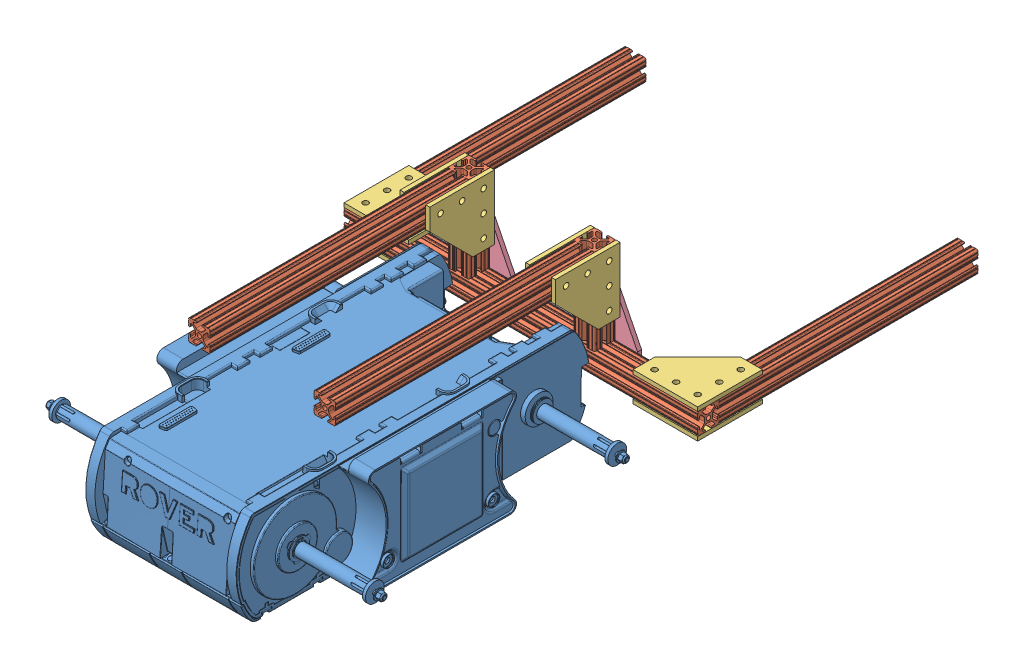
SolidWorks assembly BotAssembly, configuration Default. Lengths in mm.
Overall size (416.56 192.5 758.84).
18 component instances, 4 part files, 49 mates.
Components (placement in the parent):
- Rover Body-1: Rover Body [Default] at (125.1119 198.811 488.8206) size (400.01 131.58 418.13)
- Top Rail-1: Top Rail [Side Rail] at (51.1531 303.611 282.7206) size (25.4 25.4 304.8)
- Top Rail-3: Top Rail [Side Rail] at (199.0708 303.611 282.7206) size (25.4 25.4 304.8)
- Top Rail-5: Top Rail [Vertical Rail] at (51.1531 265.511 117.6206) x (1 0 0) z (0 1 0) size (25.4 25.4 101.6)
- Top Rail-6: Top Rail [Vertical Rail] at (199.0708 265.511 117.6206) x (1 0 0) z (0 1 0) size (25.4 25.4 101.6)
- Top Rail-7: Top Rail [Top Rail Base 16.3] at (125.1119 202.011 117.6206) x (0 1 0) z (-1 0 0) size (25.4 25.4 416.56)
- 47065T267_ALUMINUM T-SLOTTED FRAMING EXTRUSION-1: 47065T267_ALUMINUM T-SLOTTED FRAMING EXTRUSION [47065T267] at (36.0718 316.311 104.9206) x (0 0 1) z (1 0 0) size (76.2 76.2 4.76)
- 47065T267_ALUMINUM T-SLOTTED FRAMING EXTRUSION-2: 47065T267_ALUMINUM T-SLOTTED FRAMING EXTRUSION [47065T267] at (214.152 316.311 104.9206) x (0 0 1) z (1 0 0) size (76.2 76.2 4.76)
- Top Rail-8: Top Rail [Side Rail] at (320.6919 202.011 -47.4794) size (25.4 25.4 304.8)
- Top Rail-9: Top Rail [Side Rail] at (-70.4681 202.011 -47.4794) size (25.4 25.4 304.8)
- 47065T267_ALUMINUM T-SLOTTED FRAMING EXTRUSION-3: 47065T267_ALUMINUM T-SLOTTED FRAMING EXTRUSION [47065T267] at (333.3919 217.0923 130.3206) x (0 0 -1) z (0 1 0) size (76.2 76.2 4.76)
- 47065T267_ALUMINUM T-SLOTTED FRAMING EXTRUSION-4: 47065T267_ALUMINUM T-SLOTTED FRAMING EXTRUSION [47065T267] at (-83.1681 217.0923 130.3206) x (1 0 0) z (0 1 0) size (76.2 76.2 4.76)
- 47065T278_ALUMINUM T-SLOTTED FRAMING EXTRUSION-1: 47065T278_ALUMINUM T-SLOTTED FRAMING EXTRUSION [47065T278] at (160.9708 189.311 102.5393) size (76.2 76.2 4.76)
- 47065T278_ALUMINUM T-SLOTTED FRAMING EXTRUSION-2: 47065T278_ALUMINUM T-SLOTTED FRAMING EXTRUSION [47065T278] at (13.0531 189.311 102.5393) size (76.2 76.2 4.76)
- 47065T267_ALUMINUM T-SLOTTED FRAMING EXTRUSION-5: 47065T267_ALUMINUM T-SLOTTED FRAMING EXTRUSION [47065T267] at (333.3919 186.9298 130.3206) x (0 0 -1) z (0 1 0) size (76.2 76.2 4.76)
- 47065T267_ALUMINUM T-SLOTTED FRAMING EXTRUSION-6: 47065T267_ALUMINUM T-SLOTTED FRAMING EXTRUSION [47065T267] at (-83.1681 186.9298 130.3206) x (1 0 0) z (0 1 0) size (76.2 76.2 4.76)
- 47065T267_ALUMINUM T-SLOTTED FRAMING EXTRUSION-7: 47065T267_ALUMINUM T-SLOTTED FRAMING EXTRUSION [47065T267] at (66.2343 316.311 104.9206) x (0 0 1) z (1 0 0) size (76.2 76.2 4.76)
- 47065T267_ALUMINUM T-SLOTTED FRAMING EXTRUSION-8: 47065T267_ALUMINUM T-SLOTTED FRAMING EXTRUSION [47065T267] at (183.9895 316.311 104.9206) x (0 0 1) z (1 0 0) size (76.2 76.2 4.76)
Mates (geometry in assembly coordinates):
- Distance1: distance = 38.1 mm anti-aligned: plane of Rover Body-1 through (214.1119 252.811 535.67) normal (0 1 0); plane of Top Rail-1 through (41.6027 290.911 435.1206) normal (0 -1 0)
- Distance2: distance = 38.1 mm anti-aligned: plane of Top Rail-3 through (189.5203 290.911 435.1206) normal (0 -1 0); plane of Rover Body-1 through (214.1119 252.811 535.67) normal (0 1 0)
- Distance4: distance = 9.525 mm: line of Top Rail-1 through (63.8531 294.0606 435.1206) axis (0 0 -1); plane of Rover Body-1 through (55.1119 249.071 259.3206) normal (0.999848 0.017452 0)
- Distance5: distance = 9.525 mm: line of Top Rail-3 through (186.3708 294.0606 435.1206) axis (0 0 -1); plane of Rover Body-1 through (195.1119 249.071 259.3206) normal (-0.999848 0.017452 0)
- Coincident14: coincident anti-aligned: plane of Top Rail-5 through (44.7367 214.711 127.0304) normal (0 -1 0); plane of Top Rail-7 through (-83.1681 214.711 127.171) normal (0 1 0)
- Coincident15: coincident aligned: plane of Top Rail-5 through (44.82 316.311 104.9206) normal (0 0 -1); plane of Top Rail-7 through (-83.1681 211.5614 104.9206) normal (0 0 -1)
- Width1: width aligned: plane of Top Rail-7 through (333.3919 195.5946 127.0304) normal (1 0 0); plane of Top Rail-6 through (-83.1681 195.5946 127.0304) normal (-1 0 0); plane of Top Rail-7 through (211.7708 316.311 111.2875) normal (1 0 0); plane of Top Rail-5 through (38.4531 316.311 108.0702) normal (-1 0 0)
- Coincident19: coincident: plane of Top Rail-5 through (41.6027 316.311 130.3206) normal (0 0 1)
- Coincident21: coincident aligned: plane of Top Rail-1 through (60.7035 316.311 435.1206) normal (0 1 0); plane of Top Rail-5 through (44.7367 316.311 127.0304) normal (0 1 0)
- Coincident22: coincident aligned: plane of Top Rail-1 through (38.4531 313.1614 435.1206) normal (-1 0 0); plane of Top Rail-5 through (38.4531 316.311 123.9536) normal (-1 0 0)
- Coincident23: coincident aligned: plane of Top Rail-3 through (211.7708 309.9441 435.1206) normal (1 0 0); plane of Top Rail-6 through (211.7708 316.311 127.171) normal (1 0 0)
- Coincident24: coincident aligned: plane of Top Rail-3 through (192.7377 316.311 435.1206) normal (0 1 0); plane of Top Rail-6 through (192.6544 316.311 127.0304) normal (0 1 0)
- Coincident25: coincident anti-aligned: plane of Top Rail-3 through (192.6544 294.2012 130.3206) normal (0 0 -1); plane of Top Rail-6 through (189.5203 316.311 130.3206) normal (0 0 1)
- Coincident26: coincident anti-aligned: plane of Top Rail-1 through (38.4531 313.1614 435.1206) normal (-1 0 0); plane of 47065T267_ALUMINUM T-SLOTTED FRAMING EXTRUSION-1 through (38.4531 316.311 104.9206) normal (1 0 0)
- Coincident28: coincident aligned: plane of Top Rail-5 through (44.7367 316.311 127.0304) normal (0 1 0); plane of 47065T267_ALUMINUM T-SLOTTED FRAMING EXTRUSION-1 through (38.4531 316.311 181.1206) normal (0 1 0)
- Coincident29: coincident aligned: plane of Top Rail-5 through (44.82 316.311 104.9206) normal (0 0 -1); plane of 47065T267_ALUMINUM T-SLOTTED FRAMING EXTRUSION-1 through (38.4531 316.311 104.9206) normal (0 0 -1)
- Coincident30: coincident anti-aligned: plane of Top Rail-3 through (211.7708 309.9441 435.1206) normal (1 0 0); plane of 47065T267_ALUMINUM T-SLOTTED FRAMING EXTRUSION-2 through (211.7708 316.311 104.9206) normal (-1 0 0)
- Coincident31: coincident aligned: plane of Top Rail-6 through (192.6544 316.311 127.0304) normal (0 1 0); plane of 47065T267_ALUMINUM T-SLOTTED FRAMING EXTRUSION-2 through (216.5333 316.311 181.1206) normal (0 1 0)
- Coincident32: coincident aligned: plane of Top Rail-6 through (208.6212 316.311 104.9206) normal (0 0 -1); plane of 47065T267_ALUMINUM T-SLOTTED FRAMING EXTRUSION-2 through (216.5333 316.311 104.9206) normal (0 0 -1)
- Coincident34: coincident aligned: plane of Top Rail-7 through (-83.1681 214.711 111.2875) normal (0 1 0); plane of Top Rail-9 through (-60.9176 214.711 104.9206) normal (0 1 0)
- Coincident37: coincident aligned: plane of Top Rail-7 through (-83.1681 214.711 127.171) normal (0 1 0); plane of Top Rail-8 through (314.3588 214.711 104.9206) normal (0 1 0)
- Coincident39: coincident aligned: plane of Top Rail-8 through (333.3919 208.3441 104.9206) normal (1 0 0); plane of 47065T267_ALUMINUM T-SLOTTED FRAMING EXTRUSION-3 through (333.3919 219.4735 54.1206) normal (1 0 0)
- Coincident40: coincident anti-aligned: plane of Top Rail-8 through (330.2424 214.711 104.9206) normal (0 1 0); plane of 47065T267_ALUMINUM T-SLOTTED FRAMING EXTRUSION-3 through (333.3919 214.711 130.3206) normal (0 -1 0)
- Coincident42: coincident aligned: plane of Top Rail-9 through (-83.1681 211.5614 104.9206) normal (-1 0 0); plane of 47065T267_ALUMINUM T-SLOTTED FRAMING EXTRUSION-4 through (-83.1681 219.4735 130.3206) normal (-1 0 0)
- Coincident44: coincident anti-aligned: plane of Top Rail-9 through (-76.8012 214.711 104.9206) normal (0 1 0); plane of 47065T267_ALUMINUM T-SLOTTED FRAMING EXTRUSION-4 through (-83.1681 214.711 130.3206) normal (0 -1 0)
- Coincident45: coincident anti-aligned: plane of Top Rail-7 through (-83.1681 211.5614 104.9206) normal (0 0 -1); plane of 47065T278_ALUMINUM T-SLOTTED FRAMING EXTRUSION-1 through (160.9708 189.311 104.9206) normal (0 0 1)
- Coincident46: coincident anti-aligned: plane of Top Rail-7 through (-83.1681 211.5614 104.9206) normal (0 0 -1); plane of 47065T278_ALUMINUM T-SLOTTED FRAMING EXTRUSION-2 through (13.0531 189.311 104.9206) normal (0 0 1)
- Coincident47: coincident aligned: plane of Top Rail-7 through (-83.1681 189.311 108.0702) normal (0 -1 0); plane of 47065T278_ALUMINUM T-SLOTTED FRAMING EXTRUSION-1 through (237.1708 189.311 104.9206) normal (0 -1 0)
- Coincident48: coincident aligned: plane of Top Rail-7 through (-83.1681 189.311 108.0702) normal (0 -1 0); plane of 47065T278_ALUMINUM T-SLOTTED FRAMING EXTRUSION-2 through (89.2531 189.311 104.9206) normal (0 -1 0)
- Coincident53: coincident: line of 47065T267_ALUMINUM T-SLOTTED FRAMING EXTRUSION-2 through (211.7708 240.111 104.9206) axis (0 1 0); point of 47065T278_ALUMINUM T-SLOTTED FRAMING EXTRUSION-1
- Coincident54: coincident: line of 47065T267_ALUMINUM T-SLOTTED FRAMING EXTRUSION-1 through (38.4531 240.111 104.9206) axis (0 1 0); point of 47065T278_ALUMINUM T-SLOTTED FRAMING EXTRUSION-2
- Coincident55: coincident anti-aligned: plane of Top Rail-7 through (-83.1681 211.5614 104.9206) normal (0 0 -1); plane of Top Rail-9 through (-76.8845 192.6012 104.9206) normal (0 0 1)
- Coincident56: coincident aligned: plane of Top Rail-7 through (-83.1681 195.5946 127.0304) normal (-1 0 0); plane of Top Rail-9 through (-83.1681 211.5614 104.9206) normal (-1 0 0)
- Coincident57: coincident aligned: plane of Top Rail-7 through (-83.1681 208.3441 130.3206) normal (0 0 1); plane of 47065T267_ALUMINUM T-SLOTTED FRAMING EXTRUSION-4 through (-6.9681 219.4735 130.3206) normal (0 0 1)
- Coincident58: coincident anti-aligned: plane of Top Rail-7 through (-83.1681 211.5614 104.9206) normal (0 0 -1); plane of Top Rail-8 through (314.2755 192.6012 104.9206) normal (0 0 1)
- Coincident59: coincident aligned: plane of Top Rail-7 through (333.3919 195.5946 127.0304) normal (1 0 0); plane of Top Rail-8 through (333.3919 208.3441 104.9206) normal (1 0 0)
- Coincident60: coincident aligned: plane of Top Rail-7 through (-83.1681 208.3441 130.3206) normal (0 0 1); plane of 47065T267_ALUMINUM T-SLOTTED FRAMING EXTRUSION-3 through (333.3919 219.4735 130.3206) normal (0 0 1)
- Coincident61: coincident aligned: plane of 47065T267_ALUMINUM T-SLOTTED FRAMING EXTRUSION-4 through (-83.1681 219.4735 130.3206) normal (-1 0 0); plane of 47065T267_ALUMINUM T-SLOTTED FRAMING EXTRUSION-6 through (-83.1681 189.311 130.3206) normal (-1 0 0)
- Coincident62: coincident aligned: plane of 47065T267_ALUMINUM T-SLOTTED FRAMING EXTRUSION-4 through (-6.9681 219.4735 130.3206) normal (0 0 1); plane of 47065T267_ALUMINUM T-SLOTTED FRAMING EXTRUSION-6 through (-6.9681 189.311 130.3206) normal (0 0 1)
- Distance6: distance = 25.4 mm anti-aligned: plane of 47065T267_ALUMINUM T-SLOTTED FRAMING EXTRUSION-6 through (-83.1681 189.311 130.3206) normal (0 1 0); plane of 47065T267_ALUMINUM T-SLOTTED FRAMING EXTRUSION-4 through (-83.1681 214.711 130.3206) normal (0 -1 0)
- Distance7: distance = 25.4 mm anti-aligned: plane of 47065T267_ALUMINUM T-SLOTTED FRAMING EXTRUSION-3 through (333.3919 214.711 130.3206) normal (0 -1 0); plane of 47065T267_ALUMINUM T-SLOTTED FRAMING EXTRUSION-5 through (333.3919 189.311 130.3206) normal (0 1 0)
- Coincident63: coincident aligned: plane of 47065T267_ALUMINUM T-SLOTTED FRAMING EXTRUSION-3 through (333.3919 219.4735 54.1206) normal (1 0 0); plane of 47065T267_ALUMINUM T-SLOTTED FRAMING EXTRUSION-5 through (333.3919 189.311 54.1206) normal (1 0 0)
- Coincident64: coincident aligned: plane of 47065T267_ALUMINUM T-SLOTTED FRAMING EXTRUSION-3 through (333.3919 219.4735 130.3206) normal (0 0 1); plane of 47065T267_ALUMINUM T-SLOTTED FRAMING EXTRUSION-5 through (333.3919 189.311 130.3206) normal (0 0 1)
- Coincident65: coincident aligned: plane of 47065T267_ALUMINUM T-SLOTTED FRAMING EXTRUSION-2 through (216.5333 316.311 181.1206) normal (0 1 0); plane of 47065T267_ALUMINUM T-SLOTTED FRAMING EXTRUSION-8 through (186.3708 316.311 181.1206) normal (0 1 0)
- Coincident66: coincident aligned: plane of 47065T267_ALUMINUM T-SLOTTED FRAMING EXTRUSION-1 through (38.4531 316.311 181.1206) normal (0 1 0); plane of 47065T267_ALUMINUM T-SLOTTED FRAMING EXTRUSION-7 through (68.6156 316.311 181.1206) normal (0 1 0)
- Coincident67: coincident aligned: plane of 47065T267_ALUMINUM T-SLOTTED FRAMING EXTRUSION-1 through (38.4531 290.911 181.1206) normal (0 0 1); plane of 47065T267_ALUMINUM T-SLOTTED FRAMING EXTRUSION-7 through (68.6156 290.911 181.1206) normal (0 0 1)
- Coincident68: coincident aligned: plane of 47065T267_ALUMINUM T-SLOTTED FRAMING EXTRUSION-2 through (216.5333 290.911 181.1206) normal (0 0 1); plane of 47065T267_ALUMINUM T-SLOTTED FRAMING EXTRUSION-8 through (186.3708 290.911 181.1206) normal (0 0 1)
- Coincident69: coincident anti-aligned: plane of Top Rail-5 through (63.8531 316.311 111.2875) normal (1 0 0); plane of 47065T267_ALUMINUM T-SLOTTED FRAMING EXTRUSION-7 through (63.8531 316.311 104.9206) normal (-1 0 0)
- Coincident70: coincident anti-aligned: plane of Top Rail-6 through (186.3708 316.311 108.0702) normal (-1 0 0); plane of 47065T267_ALUMINUM T-SLOTTED FRAMING EXTRUSION-8 through (186.3708 316.311 104.9206) normal (1 0 0)
